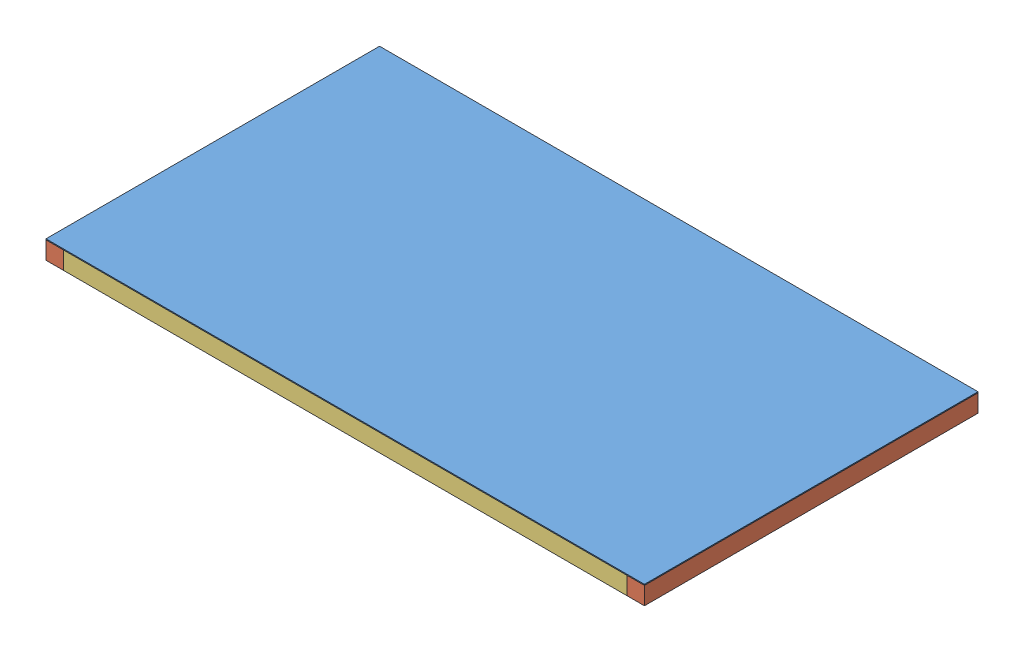
SolidWorks assembly Assemblage1, configuration Default. Lengths in mm.
Overall size (610 19 340).
5 component instances, 3 part files, 12 mates.
Components (placement in the parent):
- Vitre_cale-1: Vitre_cale [Default] at (-336.1525 48.2579 153.3134) size (610 1 340)
- linteau_18x18_L340_Marron-1: linteau_18x18_L340_Marron [Default] at (255.8475 30.2579 153.3134) size (18 18 340)
- linteau_18x18_L340_Marron-2: linteau_18x18_L340_Marron [Default] at (-336.1525 30.2579 153.3134) size (18 18 340)
- linteau_18x18_L574_Marron-1: linteau_18x18_L574_Marron [Default] at (-318.1525 30.2579 -186.6866) x (0 0 1) z (-1 0 0) size (18 18 574)
- linteau_18x18_L574_Marron-2: linteau_18x18_L574_Marron [Default] at (255.8475 30.2579 153.3134) x (0 0 -1) z (1 0 0) size (18 18 574)
Mates (geometry in assembly coordinates):
- Coïncidente1: coincident anti-aligned: plane of Vitre_cale-1 through (-336.1525 48.2579 -186.6866) normal (0 -1 0); plane of linteau_18x18_L340_Marron-2 through (-336.1525 48.2579 -186.6866) normal (0 1 0)
- Coïncidente2: coincident anti-aligned: plane of Vitre_cale-1 through (-336.1525 48.2579 -186.6866) normal (0 -1 0); plane of linteau_18x18_L340_Marron-1 through (255.8475 48.2579 -186.6866) normal (0 1 0)
- Coïncidente3: coincident aligned: plane of linteau_18x18_L340_Marron-1 through (255.8475 48.2579 153.3134) normal (0 0 1); plane of linteau_18x18_L340_Marron-2 through (-336.1525 48.2579 153.3134) normal (0 0 1)
- Coïncidente4: coincident aligned: plane of Vitre_cale-1 through (-336.1525 49.2579 153.3134) normal (0 0 1); plane of linteau_18x18_L340_Marron-1 through (255.8475 48.2579 153.3134) normal (0 0 1)
- Coïncidente5: coincident aligned: plane of Vitre_cale-1 through (273.8475 49.2579 153.3134) normal (1 0 0); plane of linteau_18x18_L340_Marron-1 through (273.8475 30.2579 -186.6866) normal (1 0 0)
- Coïncidente7: coincident aligned: plane of Vitre_cale-1 through (-336.1525 49.2579 153.3134) normal (-1 0 0); plane of linteau_18x18_L340_Marron-2 through (-336.1525 30.2579 -186.6866) normal (-1 0 0)
- Coïncidente8: coincident anti-aligned: plane of linteau_18x18_L340_Marron-2 through (-318.1525 30.2579 -186.6866) normal (1 0 0); plane of linteau_18x18_L574_Marron-1 through (-318.1525 48.2579 -186.6866) normal (-1 0 0)
- Coïncidente9: coincident aligned: plane of Vitre_cale-1 through (-336.1525 49.2579 -186.6866) normal (0 0 -1); plane of linteau_18x18_L574_Marron-1 through (255.8475 30.2579 -186.6866) normal (0 0 -1)
- Coïncidente10: coincident anti-aligned: plane of Vitre_cale-1 through (-336.1525 48.2579 -186.6866) normal (0 -1 0); plane of linteau_18x18_L574_Marron-1 through (255.8475 48.2579 -186.6866) normal (0 1 0)
- Coïncidente11: coincident anti-aligned: plane of linteau_18x18_L340_Marron-2 through (-318.1525 30.2579 -186.6866) normal (1 0 0); plane of ? through (-318.1525 25.734 153.3134) normal (-1 0 0)
- Coïncidente12: coincident aligned: plane of linteau_18x18_L340_Marron-2 through (-336.1525 48.2579 153.3134) normal (0 0 1); plane of ? through (-318.1525 7.734 153.3134) normal (0 0 1)
- Coïncidente13: coincident anti-aligned: plane of Vitre_cale-1 through (-336.1525 48.2579 -186.6866) normal (0 -1 0); plane of ? through (-318.1525 25.734 153.3134) normal (0 1 0)
